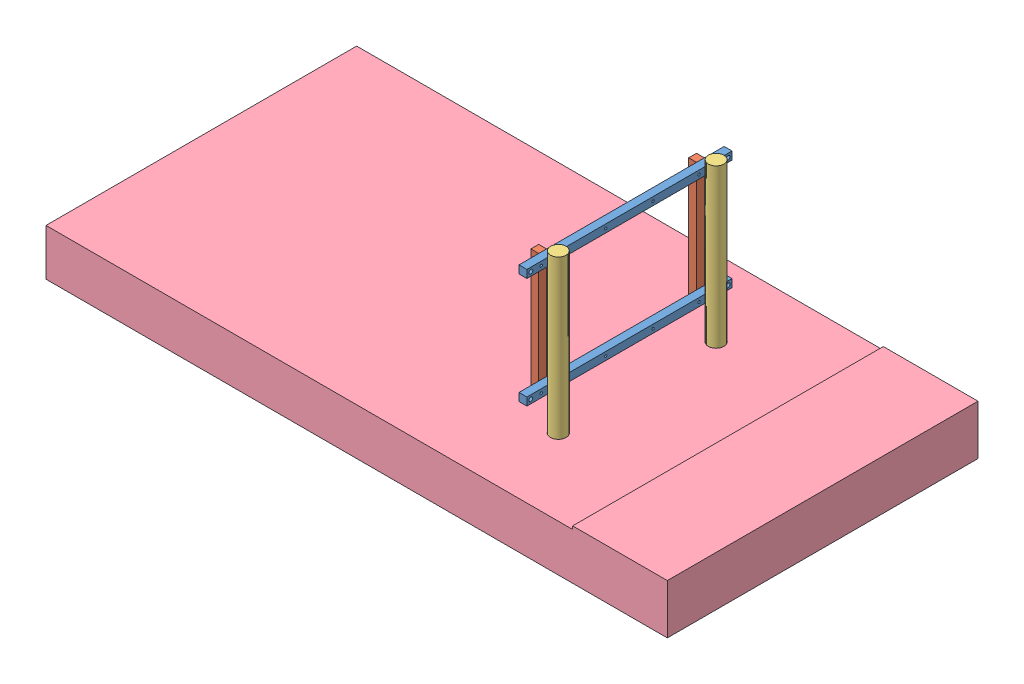
SolidWorks assembly _Tow System Assy BRAINSTORMV3FEA, configuration Default. Lengths in mm.
Overall size (2000 658 1000).
7 component instances, 4 part files, 23 mates.
Components (placement in the parent):
- Guy Wire Span BeamV3FEA-1: Guy Wire Span BeamV3FEA [Default] at (-311.0092 -340 122.54) x (-1 0 0) z (0 0 -1) size (25.4 25.4 660.4)
- Guy Wire Span BeamV3FEA-2: Guy Wire Span BeamV3FEA [Default] at (-311.0092 15.6 122.54) x (-1 0 0) z (0 0 -1) size (25.4 25.4 660.4)
- Guy Wire Vert BeamV3FEA-1: Guy Wire Vert BeamV3FEA [Default] at (-336.4092 -352.7 -461.66) x (-1 0 0) z (0 1 0) size (25.4 25.4 381)
- Guy Wire Vert BeamV3FEA-2: Guy Wire Vert BeamV3FEA [Default] at (-336.4092 -352.7 46.34) x (-1 0 0) z (0 1 0) size (25.4 25.4 381)
- 6689T606 CHROME-PLATED HARDENED 4140 ALLOY STEEL ROD 2in ODFEA-1: 6689T606 CHROME-PLATED HARDENED 4140 ALLOY STEEL ROD 2in ODFEA [6689T606] at (-273.3092 -249.9687 -461.66) x (1 0 0) z (0 1 0) size (50 50 609.6)
- 6689T606 CHROME-PLATED HARDENED 4140 ALLOY STEEL ROD 2in ODFEA-2: 6689T606 CHROME-PLATED HARDENED 4140 ALLOY STEEL ROD 2in ODFEA [6689T606] at (-273.3092 -249.9687 46.34) x (1 0 0) z (0 1 0) size (50 50 609.6)
- Pool Surface Constraints-1: Pool Surface Constraints [Default] at (-676.4092 -603.1687 -207.66) size (2000 160 1000)
Mates (geometry in assembly coordinates):
- Concentric12: concentric anti-aligned: circle of L Bracket Spacer-3; circle of 1 inch x 2 inch L bracket-6
- Concentric13: concentric anti-aligned: circle of L Bracket Spacer-3; circle of 1 inch x 2 inch L bracket-6
- Coincident329: coincident anti-aligned: plane of L Bracket Spacer-3 through (558.333 1657.0643 1927.6829) normal (-0.646537 0.60797 -0.460828); plane of 1 inch x 2 inch L bracket-6 through (600.4865 1679.6629 1898.3561) normal (0.646537 -0.60797 0.460828)
- Concentric15: concentric anti-aligned: circle of L Bracket Spacer-4; circle of 1 inch x 2 inch L bracket-5
- Concentric16: concentric anti-aligned: circle of L Bracket Spacer-4; circle of 1 inch x 2 inch L bracket-5
- Coincident330: coincident anti-aligned: plane of L Bracket Spacer-4 through (764.4476 1681.6047 1670.8822) normal (-0.646537 0.60797 -0.460828); plane of 1 inch x 2 inch L bracket-5 through (765.1438 1682.8596 1671.5609) normal (0.646537 -0.60797 0.460828)
- Coincident1957: coincident aligned: plane of Guy Wire Span BeamV3-1 through (-311.0092 -340 -537.86) normal (0 0 -1); plane of Guy Wire Span BeamV3-2 through (-311.0092 15.6 -537.86) normal (0 0 -1)
- Coincident1979: coincident aligned: plane of Guy Wire Span BeamV3-1 through (-323.7092 -352.7 -537.86) normal (-1 0 0); plane of Guy Wire Span BeamV3-2 through (-323.7092 2.9 -537.86) normal (-1 0 0)
- Coincident1989: coincident anti-aligned: plane of Guy Wire Span BeamV3-2 through (-323.7092 2.9 -537.86) normal (-1 0 0); plane of Guy Wire Vert BeamV3-1 through (-323.7092 28.3 -474.36) normal (1 0 0)
- Coincident1990: coincident aligned: plane of Guy Wire Span BeamV3-2 through (-298.3092 28.3 -537.86) normal (0 1 0); plane of Guy Wire Vert BeamV3-1 through (-336.4092 28.3 -461.66) normal (0 1 0)
- Coincident1991: coincident anti-aligned: plane of Guy Wire Span BeamV3-2 through (-323.7092 2.9 -537.86) normal (-1 0 0); plane of Guy Wire Vert BeamV3-2 through (-323.7092 28.3 33.64) normal (1 0 0)
- Coincident1992: coincident aligned: plane of Guy Wire Span BeamV3-2 through (-298.3092 28.3 -537.86) normal (0 1 0); plane of Guy Wire Vert BeamV3-2 through (-336.4092 28.3 46.34) normal (0 1 0)
- Coincident2150: coincident aligned: plane of Guy Wire Span BeamV3-1 through (-298.3092 -352.7 -537.86) normal (0 -1 0); plane of Guy Wire Vert BeamV3-1 through (-336.4092 -352.7 -461.66) normal (0 -1 0)
- Parallel40: parallel anti-aligned: plane of Guy Wire Span BeamV3-2 through (-298.3092 28.3 -537.86) normal (0 1 0); plane of 6689T606 CHROME-PLATED HARDENED 4140 ALLOY STEEL ROD 2in OD-1 through (-273.3092 -554.7687 -461.66) normal (0 -1 0)
- Tangent14: tangent anti-aligned: plane of Guy Wire Span BeamV3-1 through (-298.3092 -352.7 -537.86) normal (1 0 0); cylinder of 6689T606 CHROME-PLATED HARDENED 4140 ALLOY STEEL ROD 2in OD-1 through (-273.3092 54.8313 -461.66) axis (0 -1 0) radius 25
- Coincident2537: coincident aligned: plane of 6689T606 CHROME-PLATED HARDENED 4140 ALLOY STEEL ROD 2in OD-1 through (-273.3092 54.8313 -461.66) normal (0 1 0); plane of 6689T606 CHROME-PLATED HARDENED 4140 ALLOY STEEL ROD 2in OD-2 through (-273.3092 54.8313 46.34) normal (0 1 0)
- Tangent15: tangent anti-aligned: plane of Guy Wire Span BeamV3-2 through (-298.3092 2.9 -537.86) normal (1 0 0); cylinder of 6689T606 CHROME-PLATED HARDENED 4140 ALLOY STEEL ROD 2in OD-2 through (-273.3092 54.8313 46.34) axis (0 -1 0) radius 25
- Concentric222: concentric aligned: cylinder of Guy Wire Span BeamV3-2 through (-323.7092 15.6 46.34) axis (1 0 0) radius 2.55; cylinder of Guy Wire Vert BeamV3-2 through (-349.1092 15.6 46.34) axis (1 0 0) radius 3.5
- Concentric223: concentric aligned: cylinder of Guy Wire Span BeamV3-2 through (-323.7092 15.6 -461.66) axis (1 0 0) radius 2.55; cylinder of Guy Wire Vert BeamV3-1 through (-349.1092 15.6 -461.66) axis (1 0 0) radius 3.5
- Concentric224: concentric aligned: cylinder of 6689T606 CHROME-PLATED HARDENED 4140 ALLOY STEEL ROD 2in ODFEA-2 through (-273.3092 54.8313 46.34) axis (0 -1 0) radius 25; circle of Pool Surface Constraints-1
- Concentric225: concentric aligned: cylinder of 6689T606 CHROME-PLATED HARDENED 4140 ALLOY STEEL ROD 2in ODFEA-1 through (-273.3092 54.8313 -461.66) axis (0 -1 0) radius 25; cylinder of Pool Surface Constraints-1 through (-273.3092 -443.1687 -461.66) axis (0 -1 0) radius 25.4
- Width1: width anti-aligned: plane of Guy Wire Span BeamV3FEA-1 through (-311.0092 -340 -537.86) normal (0 0 -1); plane of Pool Surface Constraints-1 through (-311.0092 -340 122.54) normal (0 0 1); plane of Guy Wire Span BeamV3FEA-1 through (-1676.4092 -453.1687 292.34) normal (0 0 1); plane of Pool Surface Constraints-1 through (-1676.4092 -453.1687 -707.66) normal (0 0 -1)
- Distance1: distance = 101.6 mm anti-aligned: plane of 6689T606 CHROME-PLATED HARDENED 4140 ALLOY STEEL ROD 2in ODFEA-1 through (-273.3092 -554.7687 -461.66) normal (0 -1 0); plane of Pool Surface Constraints-1 through (-676.4092 -453.1687 -207.66) normal (0 1 0)
